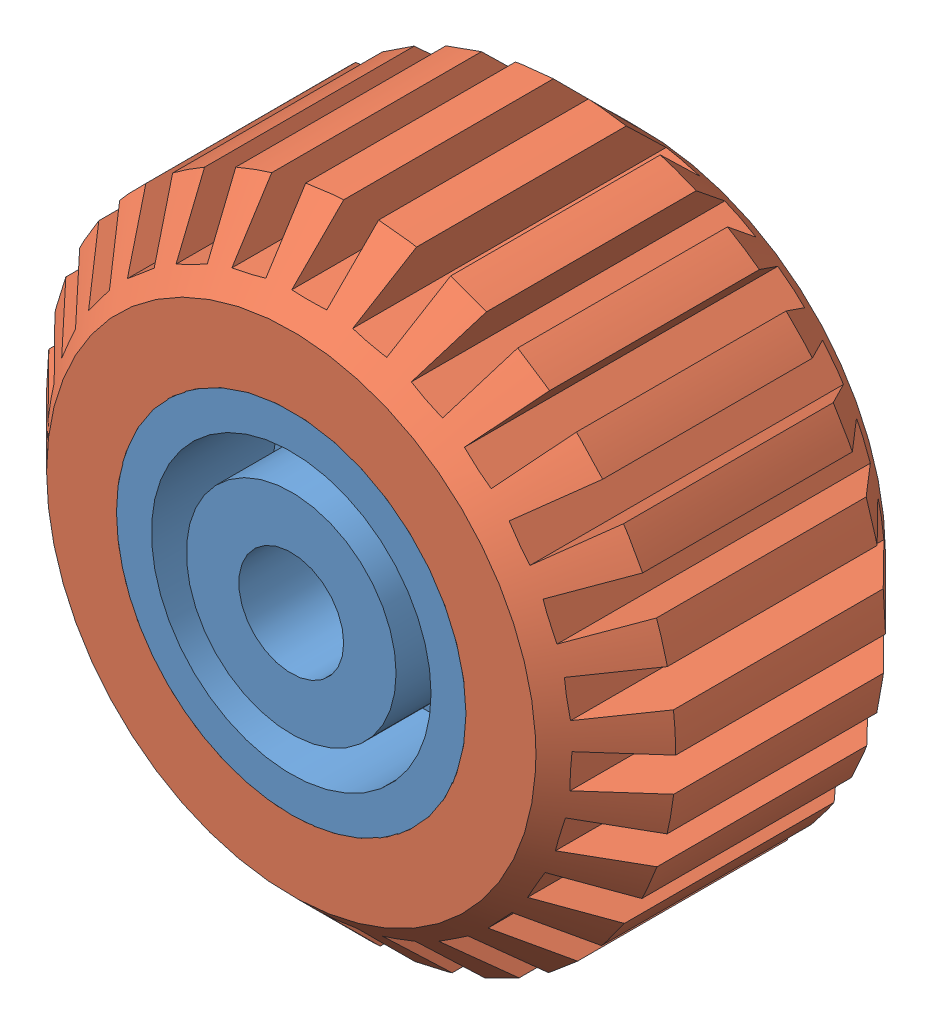
SolidWorks assembly Tyre Assembly, configuration Default. Lengths in mm.
Overall size (36 35.97 20).
2 component instances, 2 part files, 3 mates.
Components (placement in the parent):
- Part6-1: Part6 [Default] at origin size (20 20 20)
- Tyre-1: Tyre [Default] at (0 0 -5.3518) size (36 35.97 20)
Mates (geometry in assembly coordinates):
- Coincident3: coordinate: point of Part6-1
- Concentric1: concentric anti-aligned: cylinder of Part6-1 through (0 0 14.7428) axis (0 0 1) radius 10; cylinder of Tyre-1 through (0 0 9.6482) axis (0 0 -1) radius 10
- Coincident4: coincident aligned: plane of Part6-1 through (0 8 9.6482) normal (0 0 1); plane of Tyre-1 through (0 0 9.6482) normal (0 0 1)
